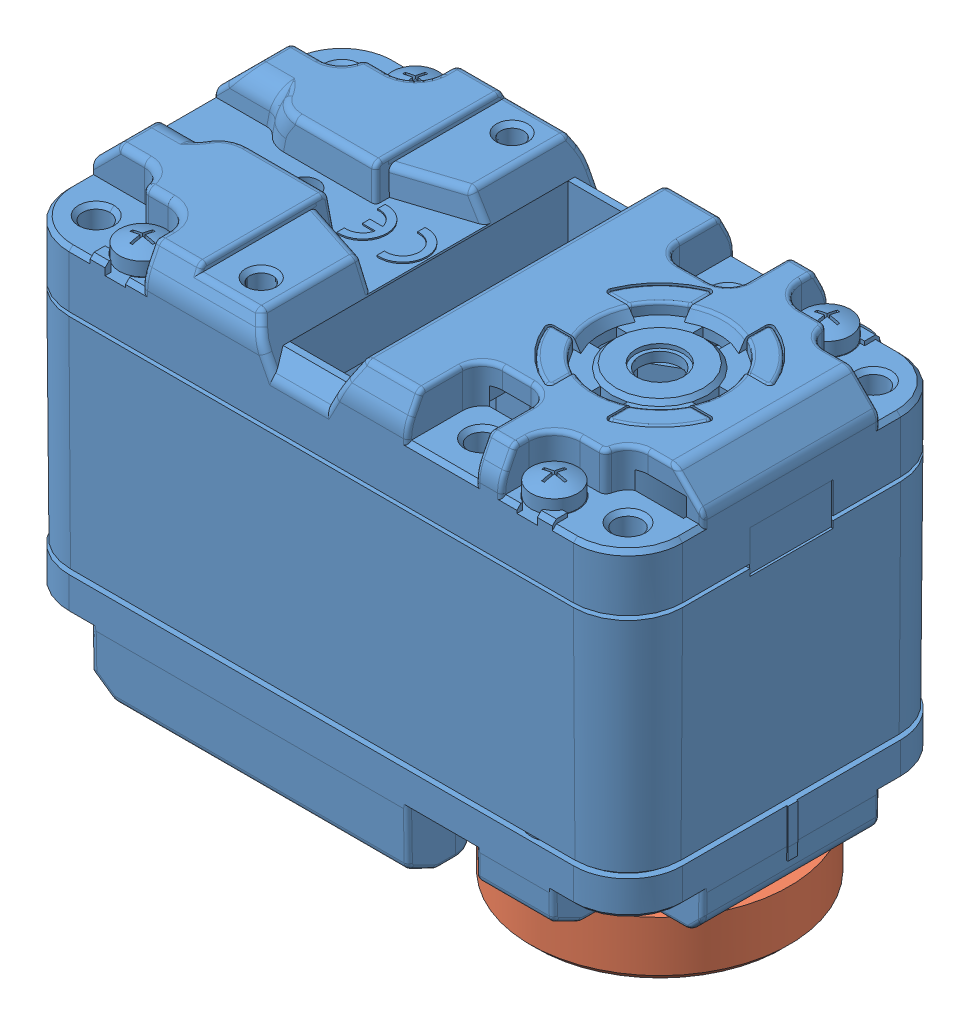
SolidWorks assembly Herkulex, configuration Default. Lengths in mm.
Overall size (47.19 35.02 24.91).
2 component instances, 2 part files, 2 mates.
Components (placement in the parent):
- Herkulex-1: Herkulex [Default] at (-20.3133 2.567 -1.4902) size (45.29 35.02 24.91)
- Herkulex horn-1: Herkulex horn [Default] at (12.6011 2.967 23.6105) x (-0.264568 0 -0.964367) z (0.964367 0 -0.264568) size (19.1 6.4 19)
Mates (geometry in assembly coordinates):
- Concentric1: concentric anti-aligned: circle of Herkulex-1; circle of Herkulex horn-1
- Coincident1: coincident anti-aligned: plane of Herkulex-1 through (15.3867 -3.433 10.5098) normal (0 -1 0); plane of Herkulex horn-1 through (5.7149 -3.433 -1.4902) normal (0 1 0)
